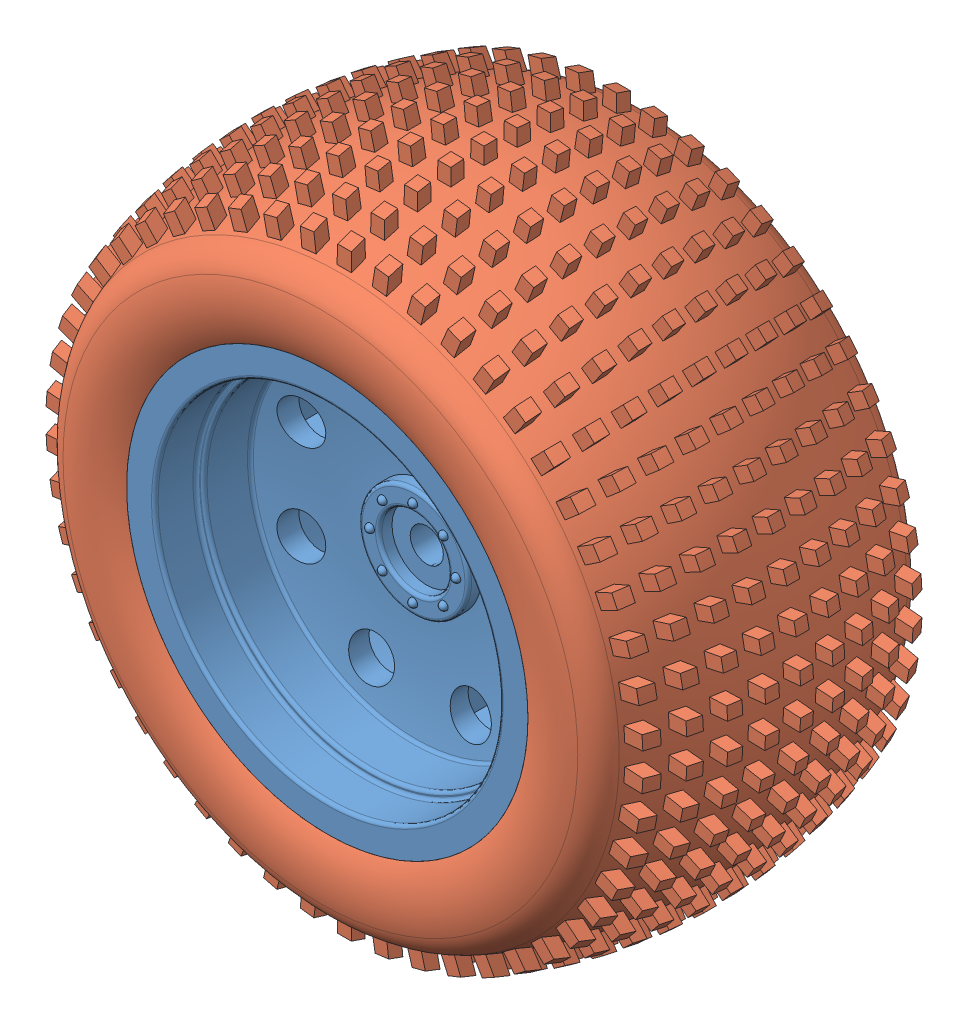
SolidWorks assembly wheel(rear wheel), configuration Default. Lengths in mm.
Overall size (99.03 99.12 50.96).
3 component instances, 3 part files, 5 mates.
Components (placement in the parent):
- 5576-1: 5576 [Default] at origin size (61.47 61.47 48.01)
- rear wheel-1: rear wheel [Default] x (0 0 -1) z (1 0 0) size (50.96 99.12 99.03)
- Part1^wheel(rear wheel)-1: Part1^wheel(rear wheel) [Default] at origin (suppressed, hidden, virtual)
Mates (geometry in assembly coordinates):
- Coincident1: coordinate: point of 5576-1
- Coincident3: coincident aligned: plane of rear wheel-1 through (0 0 0) normal (0 1 0)
- Coincident4: coincident aligned: plane of rear wheel-1 through (0 0 0) normal (1 0 0)
- Coincident5: coincident anti-aligned: plane of rear wheel-1 through (0 0 0) normal (0 0 -1)
- Coincident6: coordinate: unknown of Part1^wheel(rear wheel)-1
